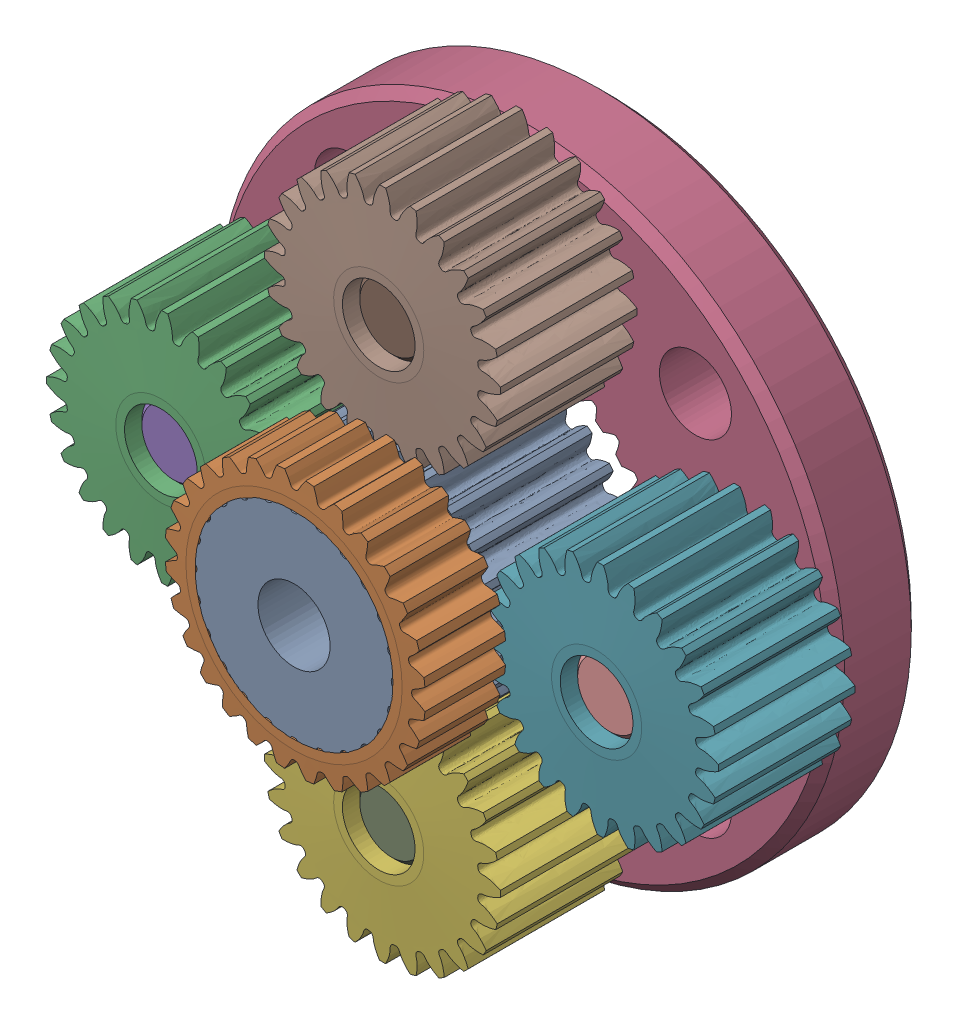
SolidWorks assembly 217-2818 Rev1, configuration Default. Lengths in mm.
Overall size (49.07 49.07 17.4).
10 component instances, 4 part files, 0 mates.
Components (placement in the parent):
- 217-2725-001 Rev1_24t Sun-1: 217-2725-001 Rev1_24t Sun [Default] at (0 0 8.7) size (14.45 14.45 12.7)
- 217-2725-002 Rev1_24t Planet-1: 217-2725-002 Rev1_24t Planet [Default] at (-12.089 0 6.35) x (-0.130526 0.991445 0) z (0 0 -1) size (13.17 13.15 8)
- 217-2724-002 Rev1-1: 217-2724-002 Rev1 [Default] x (0.707107 -0.707107 0) z (0 0 -1) size (34.7 34.7 4.7)
- 217-2625-010 Rev1-1: 217-2625-010 Rev1 [Default] at (-12.089 0 3.65) x (0.971612 -0.236582 0) z (0 0 1) size (4 4 12)
- 217-2725-002 Rev1_24t Planet-2: 217-2725-002 Rev1_24t Planet [Default] at (0 -12.089 6.35) x (-0.991445 -0.130526 0) z (0 0 -1) size (13.17 13.15 8)
- 217-2725-002 Rev1_24t Planet-3: 217-2725-002 Rev1_24t Planet [Default] at (12.089 0 6.35) x (0.130526 -0.991445 0) z (0 0 -1) size (13.17 13.15 8)
- 217-2725-002 Rev1_24t Planet-4: 217-2725-002 Rev1_24t Planet [Default] at (0 12.089 6.35) x (0.991445 0.130526 0) z (0 0 -1) size (13.17 13.15 8)
- 217-2625-010 Rev1-2: 217-2625-010 Rev1 [Default] at (0 -12.089 3.65) x (0.236582 0.971612 0) z (0 0 1) size (4 4 12)
- 217-2625-010 Rev1-3: 217-2625-010 Rev1 [Default] at (12.089 0 3.65) x (-0.971612 0.236582 0) z (0 0 1) size (4 4 12)
- 217-2625-010 Rev1-4: 217-2625-010 Rev1 [Default] at (0 12.089 3.65) x (-0.236582 -0.971612 0) z (0 0 1) size (4 4 12)
